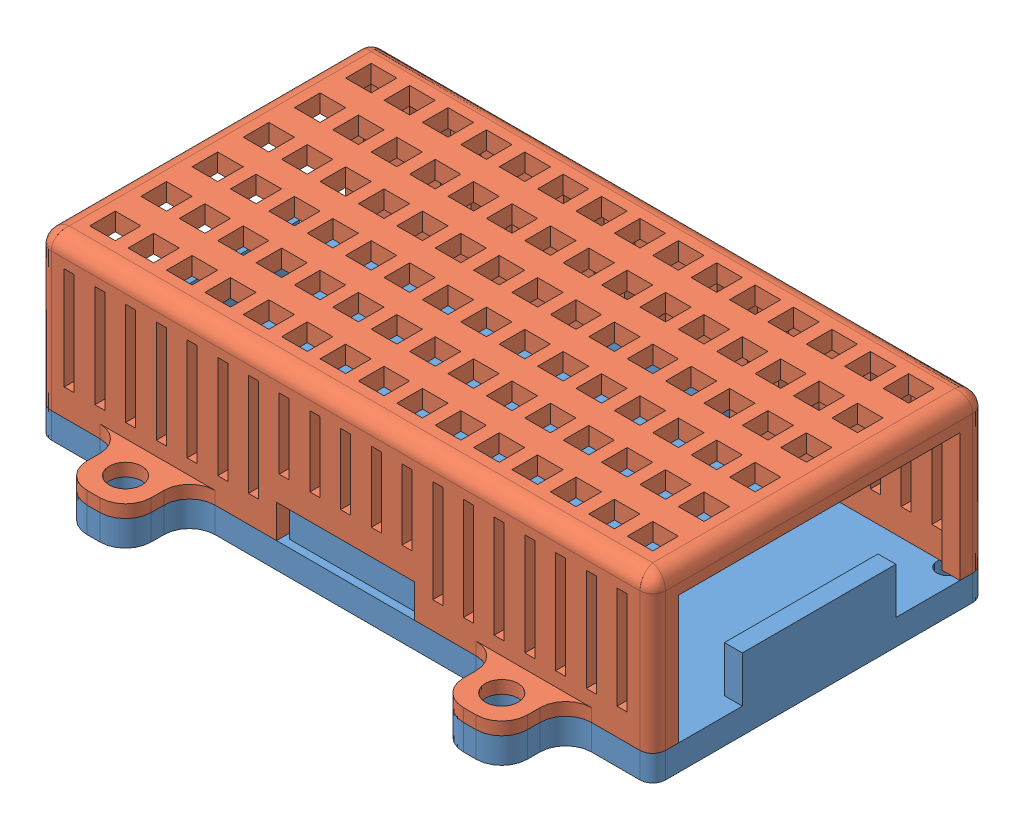
SolidWorks assembly GPS 'CAGE', configuration Default. Lengths in mm.
Overall size (120 35 90).
2 component instances, 2 part files, 3 mates.
Components (placement in the parent):
- Base-1: Base [Default] at (57.5769 57.8541 86.0562) size (120 14 90)
- Cover-1: Cover [Default] at (57.5769 62.8541 86.0562) size (120 30 90)
Mates (geometry in assembly coordinates):
- 重合1: coincident: plane of Base-1 through (57.5769 62.8541 86.0562) normal (0 1 0); plane of Cover-1 through (57.5769 62.8541 86.0562) normal (0 -1 0)
- 同心1: concentric: cylinder of Base-1 through (20.8269 57.8541 124.8062) axis (0 1 0) radius 3.2; cylinder of Cover-1 through (20.8269 92.8551 124.8062) axis (0 -1 0) radius 3.2
- 同心2: concentric: cylinder of Base-1 through (94.3269 57.8541 47.3062) axis (0 1 0) radius 3.2; cylinder of Cover-1 through (94.3269 92.8551 47.3062) axis (0 -1 0) radius 3.2
